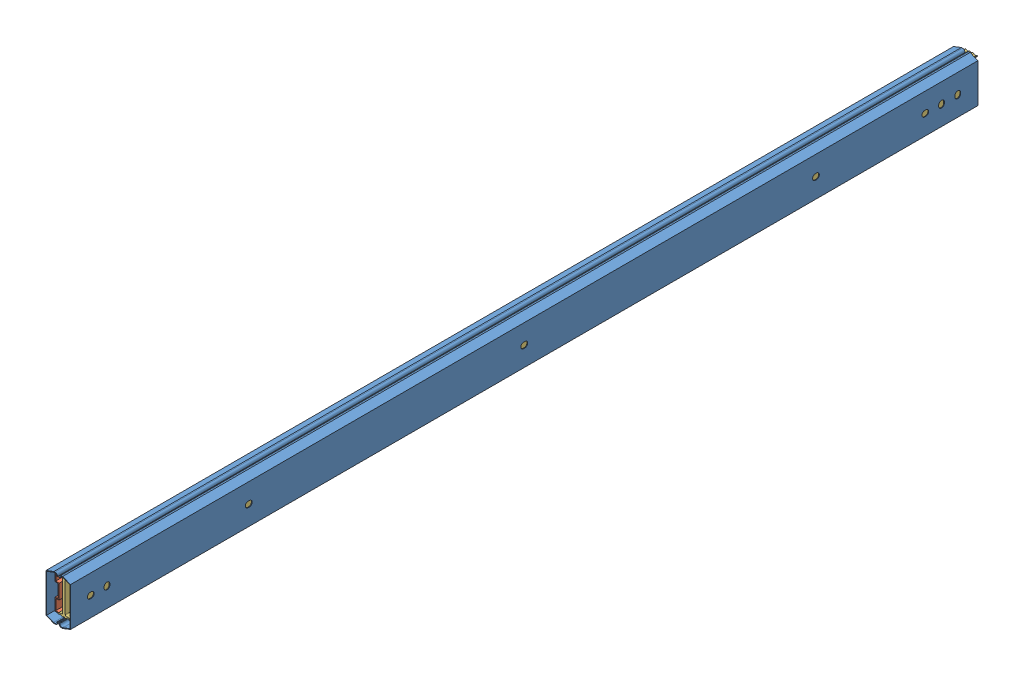
SolidWorks assembly 滑軌, configuration Default. Lengths in mm.
Overall size (19.2 35.3 715.63).
5 component instances, 3 part files, 15 mates.
Components (placement in the parent):
- C_SSRXN36Y28_3-1: C_SSRXN36Y28_3 [Default] at (16.2 32.95 807.2625) x (-1 0 0) z (0 0 1) size (7.8 34.3 203.2) (hidden)
- C_SSRXN36Y28_5-1: C_SSRXN36Y28_5 [Default] at (16.2 -2.35 711.2) x (-1 0 0) z (0 0 -1) size (9 35.3 711.2)
- C_SSRXN36Y28_3-2: C_SSRXN36Y28_3 [Default] at (-3 -2.35 502.0537) size (7.8 34.3 203.2)
- C_SSRXN36Y28_5-2: C_SSRXN36Y28_5 [Default] at (-3 -2.35 0) size (9 35.3 711.2)
- 複製 of C_SSRXN36Y28_9^滑軌-1: 複製 of C_SSRXN36Y28_9^滑軌 [Default] at (0 0 -4.432) size (9.54 28.31 711.2) (virtual)
Mates (geometry in assembly coordinates):
- 相切(T)1: tangent aligned: sphere of C_SSRXN36Y28_3-1; cylinder of C_SSRXN36Y28_5-1 through (9.55 30.6 0) axis (0 0 1) radius 1.85
- 相切(T)2: tangent aligned: sphere of C_SSRXN36Y28_3-2; cylinder of C_SSRXN36Y28_5-2 through (3.65 30.6 711.2) axis (0 0 -1) radius 1.85
- 相切(T)3: tangent aligned: cylinder of 複製 of C_SSRXN36Y28_9^滑軌-1 through (3.65 0 706.768) axis (0 0 -1) radius 1.85; sphere of C_SSRXN36Y28_3-2
- 相切(T)4: tangent aligned: sphere of C_SSRXN36Y28_3-1; cylinder of C_SSRXN36Y28_5-1 through (9.55 0 0) axis (0 0 1) radius 1.85
- 相切(T)5: tangent aligned: sphere of C_SSRXN36Y28_3-2; cylinder of C_SSRXN36Y28_5-2 through (3.65 0 711.2) axis (0 0 -1) radius 1.85
- 相切(T)6: tangent aligned: sphere of C_SSRXN36Y28_3-1; cylinder of 複製 of C_SSRXN36Y28_9^滑軌-1 through (9.55 30.6 706.768) axis (0 0 -1) radius 1.85
- 相切(T)7: tangent aligned: sphere of C_SSRXN36Y28_3-2; cylinder of 複製 of C_SSRXN36Y28_9^滑軌-1 through (3.65 30.6 706.768) axis (0 0 -1) radius 1.85
- 平行(R)1: parallel aligned: plane of C_SSRXN36Y28_5-2 through (-3 30.5467 711.2) normal (-1 0 0); plane of 複製 of C_SSRXN36Y28_9^滑軌-1 through (5.55 26.8958 706.768) normal (-1 0 0)
- 平行(R)5: parallel aligned: plane of C_SSRXN36Y28_5-2 through (4.15 -0.5 711.2) normal (0 0 1); plane of 複製 of C_SSRXN36Y28_9^滑軌-1 through (3.65 29.6 706.768) normal (0 0 1)
- 平行(R)6: parallel aligned: plane of C_SSRXN36Y28_5-1 through (9.05 -0.5 711.2) normal (0 0 1); plane of 複製 of C_SSRXN36Y28_9^滑軌-1 through (3.65 29.6 706.768) normal (0 0 1)
- 平行(R)3: parallel aligned: plane of C_SSRXN36Y28_3-2 through (1.3 9.5944 705.2537) normal (1 0 0); plane of C_SSRXN36Y28_5-2 through (-2.5 0.3959 711.2) normal (1 0 0)
- 平行(R)4: parallel aligned: plane of C_SSRXN36Y28_3-1 through (12.6 10.2331 1010.4625) normal (1 0 0); plane of C_SSRXN36Y28_3-2 through (1.3 9.5944 705.2537) normal (1 0 0)
- 限制距離1: limit distance = 0 mm aligned: plane of C_SSRXN36Y28_5-1 through (9.05 -0.5 0) normal (0 0 -1); plane of C_SSRXN36Y28_5-2 through (4.15 -0.5 0) normal (0 0 -1)
- 限制距離3: limit distance = 4.432 mm aligned: plane of 複製 of C_SSRXN36Y28_9^滑軌-1 through (3.65 29.6 706.768) normal (0 0 1); plane of C_SSRXN36Y28_5-1 through (9.05 -0.5 711.2) normal (0 0 1)
- 限制距離4: limit distance = 4.432 mm aligned: plane of 複製 of C_SSRXN36Y28_9^滑軌-1 through (3.65 29.6 706.768) normal (0 0 1); plane of C_SSRXN36Y28_5-1 through (9.05 -0.5 711.2) normal (0 0 1)
